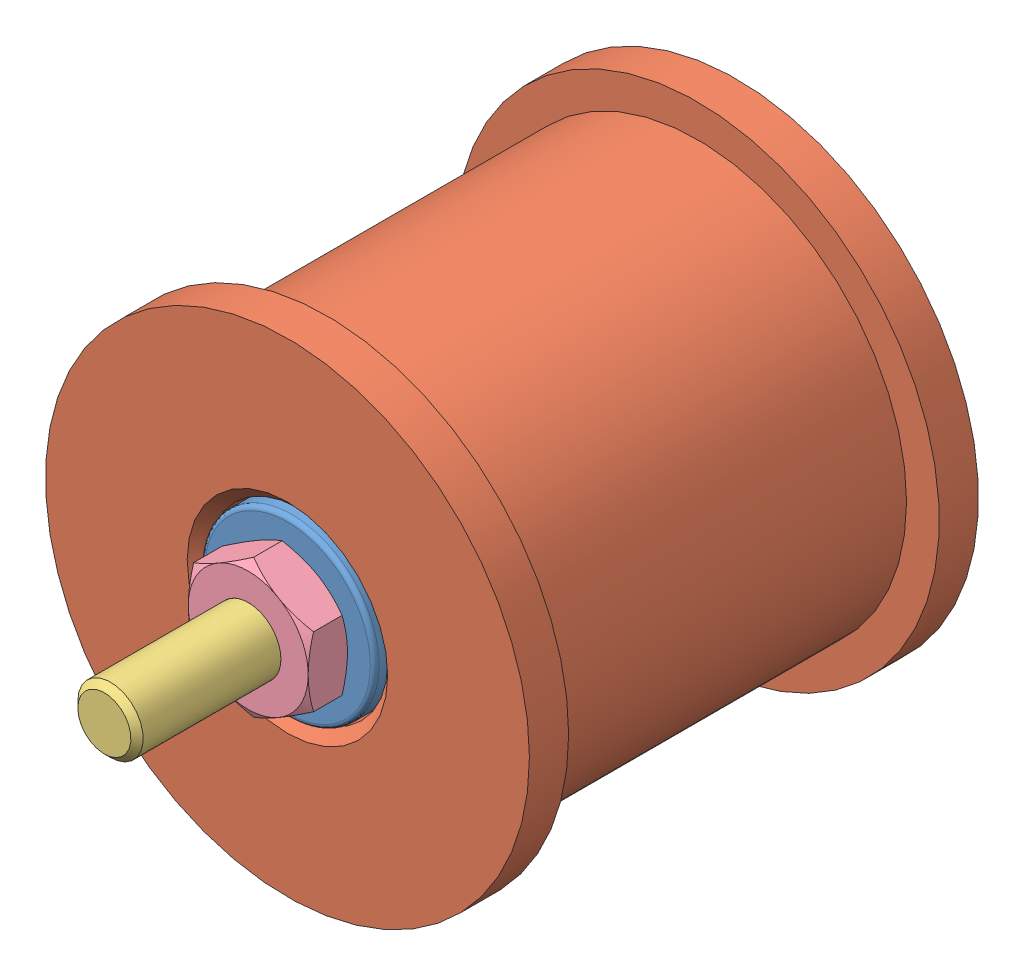
SolidWorks assembly Baugruppe_Laufrad, configuration Standard. Lengths in mm.
Overall size (22.2 22.2 29).
4 component instances, 4 part files, 6 mates.
Components (placement in the parent):
- Kugellager_8x3x4-1: Kugellager_8x3x4 [Standard] at (-0.0094 0.0608 6) size (8 8 4)
- Laufrad-1: Laufrad [Standard] at (-0.0094 0.0608 -0.3) size (22.2 22.2 20.6)
- socket head cap screw_iso-1: socket head cap screw_iso [ISO 4762 M3 x 16 - 16N] at (-0.0094 0.0608 -0.6) x (0 0 1) z (-0.076385 0.997078 0) size (19 5.5 5.5)
- hex thin nut chamfered gradeab_iso-2: hex thin nut chamfered gradeab_iso [ISO - 4035 - M3 - N] at (-0.0094 0.0608 11.8) size (5.5 6.35 1.8)
Mates (geometry in assembly coordinates):
- Deckungsgleich1: coincident anti-aligned: plane of Kugellager_8x3x4-1 through (-0.0094 0.0608 6) normal (0 0 -1); plane of Laufrad-1 through (-0.0094 1.5608 6) normal (0 0 1)
- Konzentrisch2: concentric aligned: cylinder of Kugellager_8x3x4-1 through (-0.0094 0.0608 10) axis (0 0 -1) radius 1.5; cylinder of Laufrad-1 through (-0.0094 0.0608 -10.1) axis (0 0 -1) radius 1.5
- Konzentrisch3: concentric aligned: cylinder of Kugellager_8x3x4-1 through (-0.0094 0.0608 10) axis (0 0 -1) radius 1.5; cylinder of Schraube_M3-1 through (-0.0094 0.0608 -32.35) axis (0 0 -1) radius 1.5
- Deckungsgleich2: coincident anti-aligned: plane of Laufrad-1 through (-0.0094 6.0608 2.4) normal (0 0 -1); plane of Schraube_M3-1 through (2.7326 0.2709 2.4) normal (0 0 1)
- Konzentrisch5: concentric anti-aligned: cylinder of Schraube_M3-1 through (-0.0094 0.0608 -32.35) axis (0 0 -1) radius 1.5; cylinder of Mutter_M3-2 through (-0.0094 0.0608 10) axis (0 0 1) radius 1.25
- Deckungsgleich4: coincident anti-aligned: plane of Kugellager_8x3x4-1 through (-0.0094 0.0608 10) normal (0 0 1); plane of Mutter_M3-2 through (-0.0094 3.2363 10) normal (0 0 -1)
